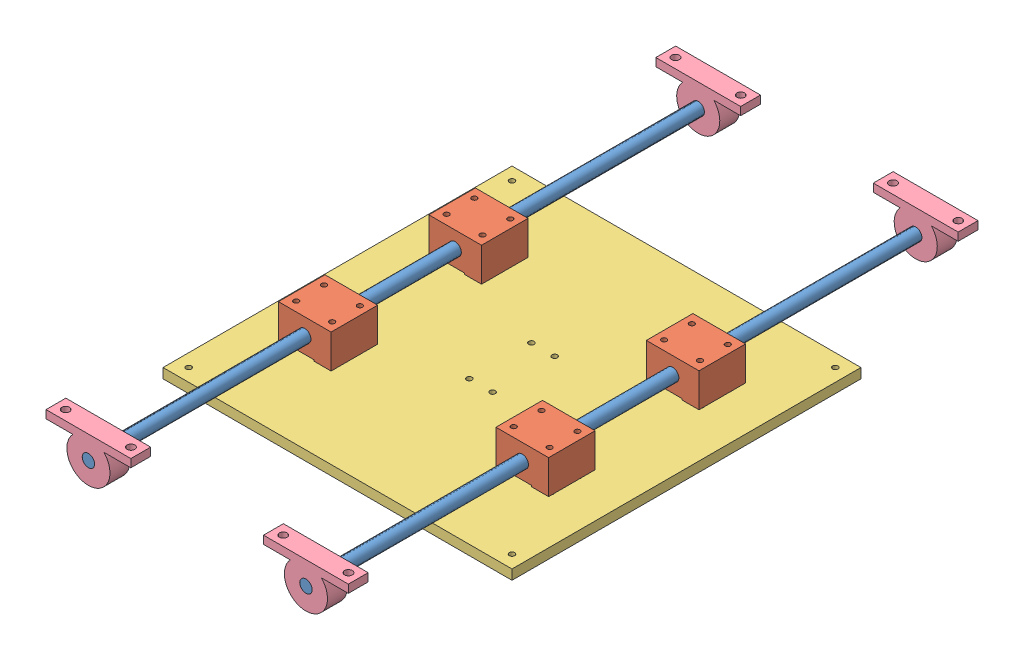
SolidWorks assembly zAssembly, configuration Default. Lengths in mm.
Overall size (225 35.62 406).
11 component instances, 4 part files, 33 mates.
Components (placement in the parent):
- longRods-1: longRods [Default] at (182.62 20.815 315.5) x (-0.927984 0.372621 0) z (-0.372621 -0.927984 0) size (8 406 8)
- silverSlider-1: silverSlider [Default] at (165.64 31.315 79.03) x (0 0 -1) z (-1 0 0) size (30.03 21.79 33.96)
- longRods-2: longRods [Default] at (42.38 20.815 315.5) x (0.958698 -0.284426 0) z (0.284426 0.958698 0) size (8 406 8)
- silverSlider-2: silverSlider [Default] at (25.4 31.315 79.03) x (0 0 -1) z (-1 0 0) size (30.03 21.79 33.96)
- silverSlider-3: silverSlider [Default] at (25.4 31.315 176) x (0 0 -1) z (-1 0 0) size (30.03 21.79 33.96)
- silverSlider-4: silverSlider [Default] at (165.64 31.315 176) x (0 0 -1) z (-1 0 0) size (30.03 21.79 33.96)
- baseZBoard-1: baseZBoard [Default] at (0 0 225) size (225 6.35 225)
- cloudPillowThing-1: cloudPillowThing [Default] at (155.27 35.615 -77.7) x (1 0 0) z (0 1 0) size (54.7 12.8 28.7)
- cloudPillowThing-2: cloudPillowThing [Default] at (15.03 35.615 -77.7) x (1 0 0) z (0 1 0) size (54.7 12.8 28.7)
- cloudPillowThing-3: cloudPillowThing [Default] at (15.03 35.615 315.5) x (1 0 0) z (0 1 0) size (54.7 12.8 28.7)
- cloudPillowThing-4: cloudPillowThing [Default] at (155.27 35.615 315.5) x (1 0 0) z (0 1 0) size (54.7 12.8 28.7)
Mates (geometry in assembly coordinates):
- Coincident1: coincident anti-aligned: cylinder of longRods-1 through (182.62 20.815 -90.5) axis (0 0 1) radius 4; circle of silverSlider-1
- Concentric1: concentric anti-aligned: cylinder of longRods-2 through (42.38 20.815 -90.5) axis (0 0 1) radius 4; cylinder of silverSlider-3 through (42.38 20.815 176) axis (0 0 -1) radius 4
- Coincident2: coincident anti-aligned: cylinder of longRods-2 through (42.38 20.815 -90.5) axis (0 0 1) radius 4; circle of silverSlider-2
- Coincident3: coincident anti-aligned: cylinder of longRods-1 through (182.62 20.815 -90.5) axis (0 0 1) radius 4; circle of silverSlider-4
- Coincident4: coincident: plane of silverSlider-1 through (199.6 9.525 79.03) normal (1 0 0); line of silverSlider-4 through (199.6 9.525 176) axis (0 1 0)
- Coincident5: coincident aligned: plane of silverSlider-2 through (59.36 9.525 79.03) normal (1 0 0); plane of silverSlider-3 through (59.36 9.525 176) normal (1 0 0)
- Coincident6: coincident aligned: plane of silverSlider-1 through (165.64 10.325 79.03) normal (0 -1 0); plane of silverSlider-2 through (25.4 10.325 79.03) normal (0 -1 0)
- Coincident7: coincident aligned: plane of silverSlider-1 through (165.64 9.525 49) normal (0 0 -1); plane of silverSlider-2 through (25.4 9.525 49) normal (0 0 -1)
- Coincident8: coincident aligned: plane of silverSlider-3 through (25.4 9.525 145.97) normal (0 0 -1); plane of silverSlider-4 through (165.64 9.525 145.97) normal (0 0 -1)
- Distance4: distance = 3.175 mm anti-aligned: plane of silverSlider-4 through (165.64 9.525 176) normal (0 -1 0); plane of baseZBoard-1 through (0 6.35 225) normal (0 1 0)
- Parallel1: parallel aligned: plane of silverSlider-2 through (25.4 9.525 49) normal (0 0 -1); plane of baseZBoard-1 through (0 6.35 0) normal (0 0 -1)
- Coincident13: coincident anti-aligned: plane of longRods-2 through (42.38 20.815 -90.5) normal (0 0 -1); plane of ? through (123.0719 445.2288 236.0179) normal (0 -1 0)
- Width1: width anti-aligned: plane of silverSlider-3 through (59.36 9.525 176) normal (1 0 0); plane of baseZBoard-1 through (165.64 9.525 176) normal (-1 0 0); plane of silverSlider-4 through (0 6.35 225) normal (-1 0 0); plane of baseZBoard-1 through (225 6.35 225) normal (1 0 0)
- Width2: width anti-aligned: plane of silverSlider-3 through (25.4 9.525 176) normal (0 0 1); plane of baseZBoard-1 through (25.4 9.525 49) normal (0 0 -1); plane of silverSlider-2 through (0 6.35 0) normal (0 0 -1); plane of baseZBoard-1 through (0 6.35 225) normal (0 0 1)
- Distance2: distance = 127 mm anti-aligned: plane of silverSlider-4 through (165.64 9.525 176) normal (0 0 1); plane of silverSlider-1 through (165.64 9.525 49) normal (0 0 -1)
- Distance3: distance = 25.4 mm aligned: plane of silverSlider-3 through (25.4 9.525 176) normal (-1 0 0); plane of baseZBoard-1 through (0 6.35 225) normal (-1 0 0)
- Concentric4: concentric aligned: cylinder of longRods-1 through (182.62 20.815 -90.5) axis (0 0 1) radius 4; cylinder of cloudPillowThing-1 through (182.62 20.815 -90.5) axis (0 0 1) radius 4
- Parallel2: parallel anti-aligned: line of baseZBoard-1 through (225 225 6.35) axis (0 -1 0); line of cloudPillowThing-1 through (155.27 35.615 -90.5) axis (1 0 0)
- Coincident15: coincident aligned: plane of cloudPillowThing-1 through (155.27 35.615 -90.5) normal (0 1 0); plane of cloudPillowThing-2 through (15.03 35.615 -90.5) normal (0 1 0)
- Coincident16: coincident: line of cloudPillowThing-1 through (155.27 35.615 -90.5) axis (1 0 0); plane of cloudPillowThing-4 through (155.27 35.615 302.7) normal (0 1 0)
- Coincident17: coincident: line of cloudPillowThing-2 through (15.03 35.615 -90.5) axis (1 0 0); plane of cloudPillowThing-3 through (15.03 35.615 302.7) normal (0 1 0)
- Coincident18: coincident anti-aligned: circle of longRods-2; cylinder of cloudPillowThing-2 through (42.38 20.815 -90.5) axis (0 0 1) radius 4
- Concentric5: concentric aligned: cylinder of longRods-2 through (42.38 20.815 -90.5) axis (0 0 1) radius 4; cylinder of cloudPillowThing-3 through (42.38 20.815 302.7) axis (0 0 1) radius 4
- Coincident19: coincident anti-aligned: cylinder of longRods-1 through (182.62 20.815 -90.5) axis (0 0 1) radius 4; circle of cloudPillowThing-4
- Coincident20: coincident aligned: plane of longRods-1 through (182.62 20.815 315.5) normal (0 0 1); plane of cloudPillowThing-4 through (182.62 20.815 315.5) normal (0 0 1)
- Coincident21: coincident aligned: plane of longRods-2 through (42.38 20.815 315.5) normal (0 0 1); plane of cloudPillowThing-3 through (42.38 20.815 315.5) normal (0 0 1)
- Coincident22: coincident aligned: plane of longRods-1 through (182.62 20.815 -90.5) normal (0 0 -1); plane of cloudPillowThing-1 through (182.62 20.815 -90.5) normal (0 0 -1)
- Coincident23: coincident aligned: plane of longRods-2 through (42.38 20.815 -90.5) normal (0 0 -1); plane of cloudPillowThing-2 through (42.38 20.815 -90.5) normal (0 0 -1)
- Coincident24: coincident aligned: plane of cloudPillowThing-1 through (182.62 20.815 -90.5) normal (0 0 -1); plane of cloudPillowThing-2 through (42.38 20.815 -90.5) normal (0 0 -1)
- Width3: width anti-aligned: plane of baseZBoard-1 through (0 6.35 225) normal (0 0 1); plane of cloudPillowThing-2 through (0 6.35 0) normal (0 0 -1); plane of baseZBoard-1 through (42.38 20.815 -90.5) normal (0 0 -1); plane of cloudPillowThing-3 through (42.38 20.815 315.5) normal (0 0 1)
- Coincident29: coincident anti-aligned: plane of baseZBoard-1 through (0 0 225) normal (0 -1 0); plane of assembly through (0 0 0) normal (0 1 0)
- Coincident30: coincident anti-aligned: plane of baseZBoard-1 through (0 6.35 225) normal (-1 0 0); plane of assembly through (0 0 0) normal (1 0 0)
- Coincident28: coincident anti-aligned: plane of baseZBoard-1 through (0 6.35 0) normal (0 0 -1); plane of assembly through (0 0 0) normal (0 0 1)
